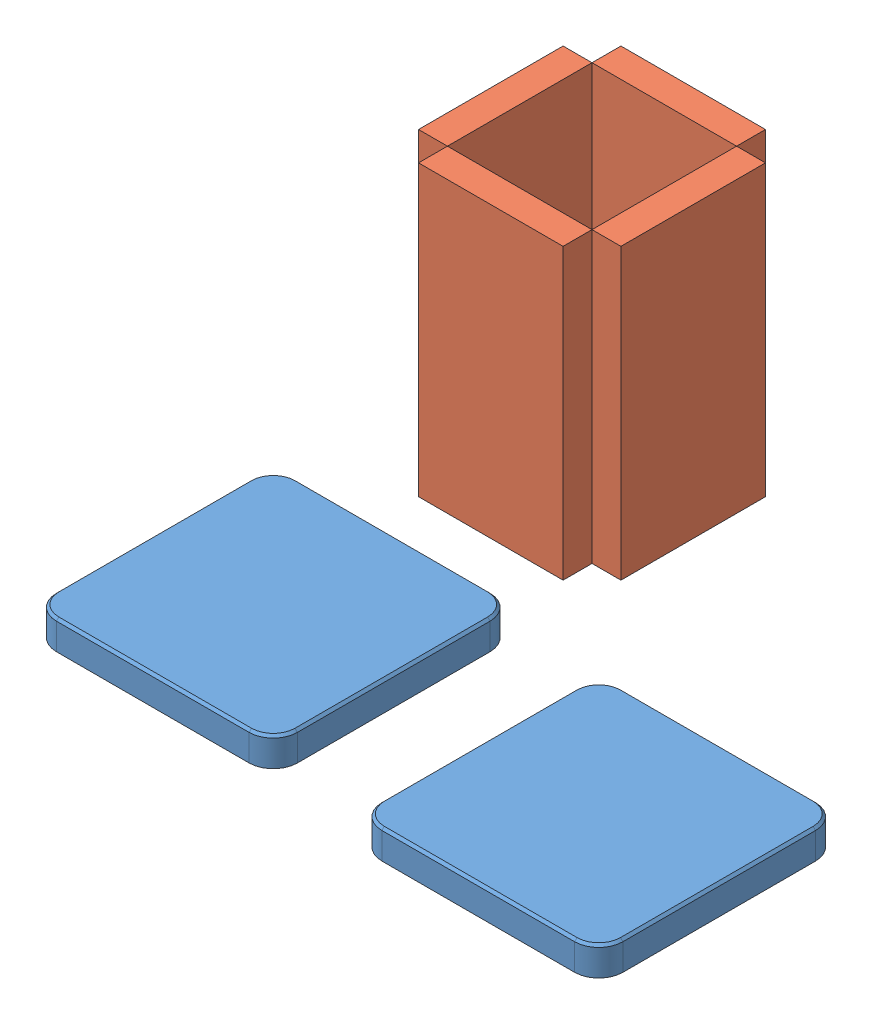
SolidWorks assembly P59, configuration Predeterminado. Lengths in mm.
Overall size (221.35 162.79 353.64).
6 component instances, 2 part files, 8 mates.
Components (placement in the parent):
- P59.1-1: P59.1 [Predeterminado] at origin size (100 12 100)
- P59.1-2: P59.1 [Predeterminado] at (8.0028 150.785 143.0897) size (100 12 100)
- P59.2-1: P59.2 [Predeterminado] at (-121.3493 72 -148.5516) x (0 0 -1) z (1 0 0) size (12 120 60)
- P59.2-2: P59.2 [Predeterminado] at (-91.3493 72 -118.5516) size (12 120 60)
- P59.2-3: P59.2 [Predeterminado] at (-163.3493 72 -118.5516) size (12 120 60)
- P59.2-4: P59.2 [Predeterminado] at (-121.3493 72 -76.5516) x (0 0 -1) z (1 0 0) size (12 120 60)
Mates (geometry in assembly coordinates):
- Coincidente1: coordinate: point of P59.1-1
- Coincidente2: coincident anti-aligned: plane of P59.1-1 through (40 12 -40) normal (0 1 0); plane of P59.2-1 through (-91.3493 12 -160.5516) normal (0 -1 0)
- Coincidente5: coincident anti-aligned: line of P59.2-3 through (-151.3493 90.2423 -88.5516) axis (0 -1 0); line of P59.2-4 through (-151.3493 -29.7577 -88.5516) axis (0 1 0)
- Coincidente6: coincident: point of P59.2-3; point of P59.2-4
- Coincidente7: coincident aligned: line of P59.2-2 through (-91.3493 90.2423 -88.5516) axis (0 -1 0); line of P59.2-4 through (-91.3493 90.2423 -88.5516) axis (0 -1 0)
- Coincidente8: coincident: point of P59.2-2; point of P59.2-4
- Coincidente9: coincident anti-aligned: line of P59.2-1 through (-91.3493 132 -148.5516) axis (0 -1 0); line of P59.2-2 through (-91.3493 12 -148.5516) axis (0 1 0)
- Coincidente10: coincident: point of P59.2-1; point of P59.2-2
